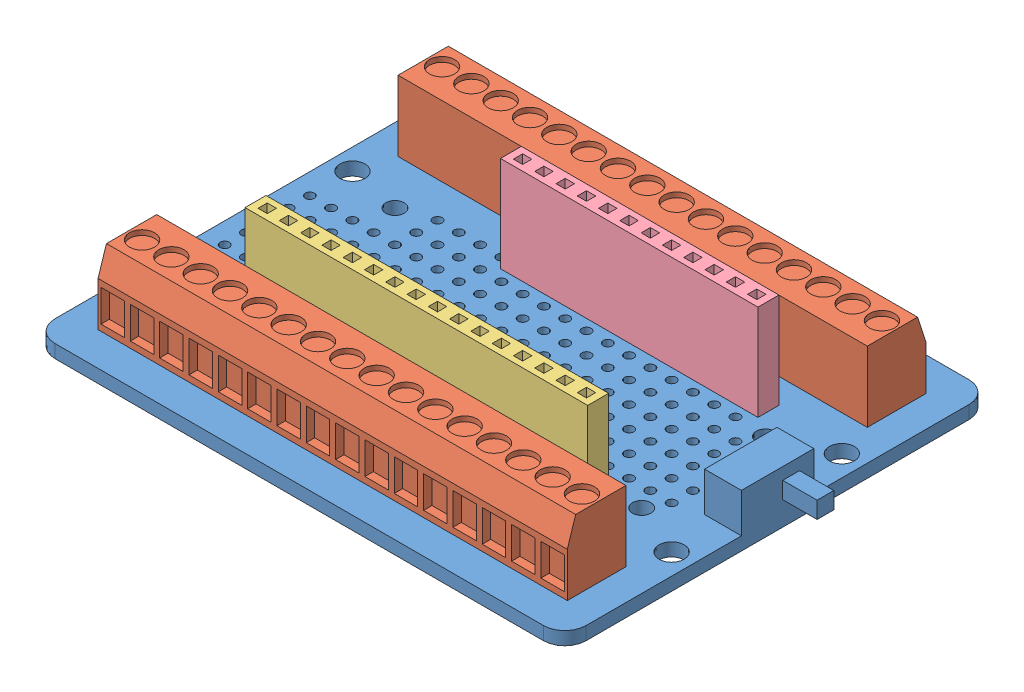
SolidWorks assembly screw_terminal_16x_3.5pitch, configuration Default. Lengths in mm.
Overall size (67.5 15.2 50.8).
5 component instances, 4 part files, 9 mates.
Components (placement in the parent):
- 2926 Terminal Block Breakout FeatherWing-1: 2926 Terminal Block Breakout FeatherWing [Default] at origin size (67.5 6.27 50.8)
- screw_terminal_16x_3.5pitch-1: screw_terminal_16x_3.5pitch [Default] at (-28 1.57 14.4) x (0 0 1) z (-1 0 0) size (7 12.2 56)
- screw_terminal_16x_3.5pitch-2: screw_terminal_16x_3.5pitch [Default] at (28 1.57 -14.4) x (0 0 -1) z (1 0 0) size (7 12.2 56)
- header_f16_tall-1: header_f16_tall [Default] at (-20.445 1.57 10.16) size (40.89 11.4 2.5)
- header_f12_tall-1: header_f12_tall [Default] at (-10.285 1.57 -10.16) size (30.73 14.4 2.5)
Mates (geometry in assembly coordinates):
- Coincident4: coincident anti-aligned: plane of 2926 Terminal Block Breakout FeatherWing-1 through (0 0 0) normal (1 0 0); plane of screw_terminal_16x_3.5pitch-1 through (0 1.57 14.4) normal (-1 0 0)
- Coincident5: coincident anti-aligned: plane of 2926 Terminal Block Breakout FeatherWing-1 through (0 1.57 0) normal (0 1 0); plane of screw_terminal_16x_3.5pitch-1 through (28 1.57 21.4) normal (0 -1 0)
- Distance1: distance = 11 mm anti-aligned: plane of screw_terminal_16x_3.5pitch-1 through (28 1.57 14.4) normal (0 0 -1); plane of 2926 Terminal Block Breakout FeatherWing-1 through (-31.7 1.57 25.4) normal (0 0 1)
- Concentric1: concentric aligned: cylinder of 2926 Terminal Block Breakout FeatherWing-1 through (-19.05 1.57 10.16) axis (0 -1 0) radius 0.55; line of header_f16_tall-1 through (-19.05 1.57 10.16) axis (0 -1 0)
- Concentric2: concentric aligned: cylinder of 2926 Terminal Block Breakout FeatherWing-1 through (19.05 1.57 10.16) axis (0 -1 0) radius 0.55; line of header_f16_tall-1 through (19.05 1.57 10.16) axis (0 -1 0)
- Coincident7: coincident anti-aligned: plane of 2926 Terminal Block Breakout FeatherWing-1 through (0 1.57 0) normal (0 1 0); plane of header_f16_tall-1 through (-20.445 1.57 11.41) normal (0 -1 0)
- Concentric3: concentric aligned: cylinder of 2926 Terminal Block Breakout FeatherWing-1 through (19.05 1.57 -10.16) axis (0 -1 0) radius 0.55; line of header_f12_tall-1 through (19.05 1.57 -10.16) axis (0 -1 0)
- Concentric4: concentric aligned: cylinder of 2926 Terminal Block Breakout FeatherWing-1 through (-8.89 1.57 -10.16) axis (0 -1 0) radius 0.55; line of header_f12_tall-1 through (-8.89 1.57 -10.16) axis (0 -1 0)
- Coincident8: coincident anti-aligned: plane of 2926 Terminal Block Breakout FeatherWing-1 through (0 1.57 0) normal (0 1 0); plane of header_f12_tall-1 through (-10.285 1.57 -8.91) normal (0 -1 0)
